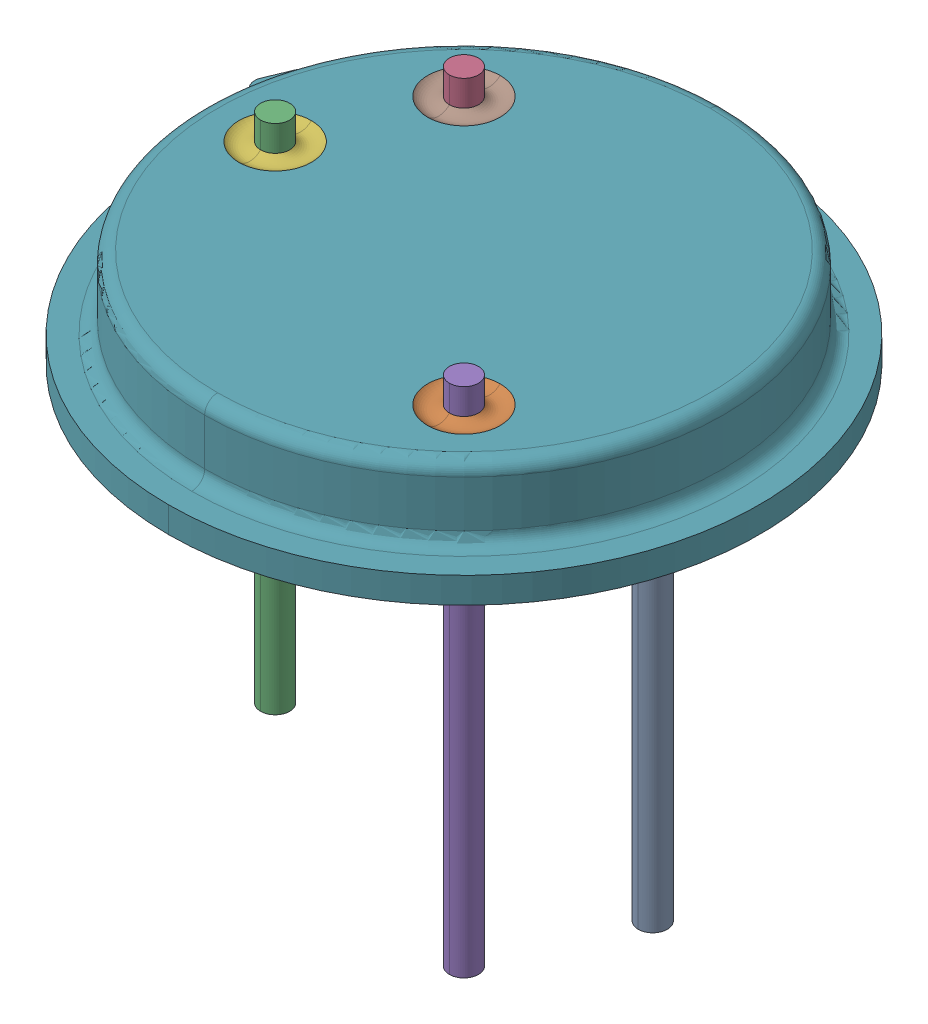
SolidWorks assembly ASM0001_ASM.stp, configuration Default. Lengths in mm.
Overall size (9.59 7.92 9.14).
8 component instances, 4 part files, 0 mates.
Components (placement in the parent):
- PRT0005.stp-1: PRT0005.stp [Default] at (3.2095 -9.0643 9.2292) size (0.7 6.15 0.7)
- PRT0006.stp-1: PRT0006.stp [Default] at (2.3542 -3.1643 11.2939) size (1.12 1.62 1.12)
- PRT0007.stp-1: PRT0007.stp [Default] at (-2.6305 -9.0643 9.2292) size (0.45 7.92 0.45)
- PRT0007.stp-2: PRT0007.stp [Default] at (-1.7753 -9.0643 7.1644) size (0.45 7.92 0.45)
- PRT0007.stp-3: PRT0007.stp [Default] at (2.3542 -9.0643 11.2939) size (0.45 7.92 0.45)
- PRT0006.stp-2: PRT0006.stp [Default] at (-2.6305 -3.1643 9.2292) size (1.12 1.62 1.12)
- PRT0008.stp-1: PRT0008.stp [Default] at (0.2895 -3.0643 9.2292) size (9.59 1.52 9.14)
- PRT0006.stp-3: PRT0006.stp [Default] at (-1.7753 -3.1643 7.1644) size (1.12 1.62 1.12)
